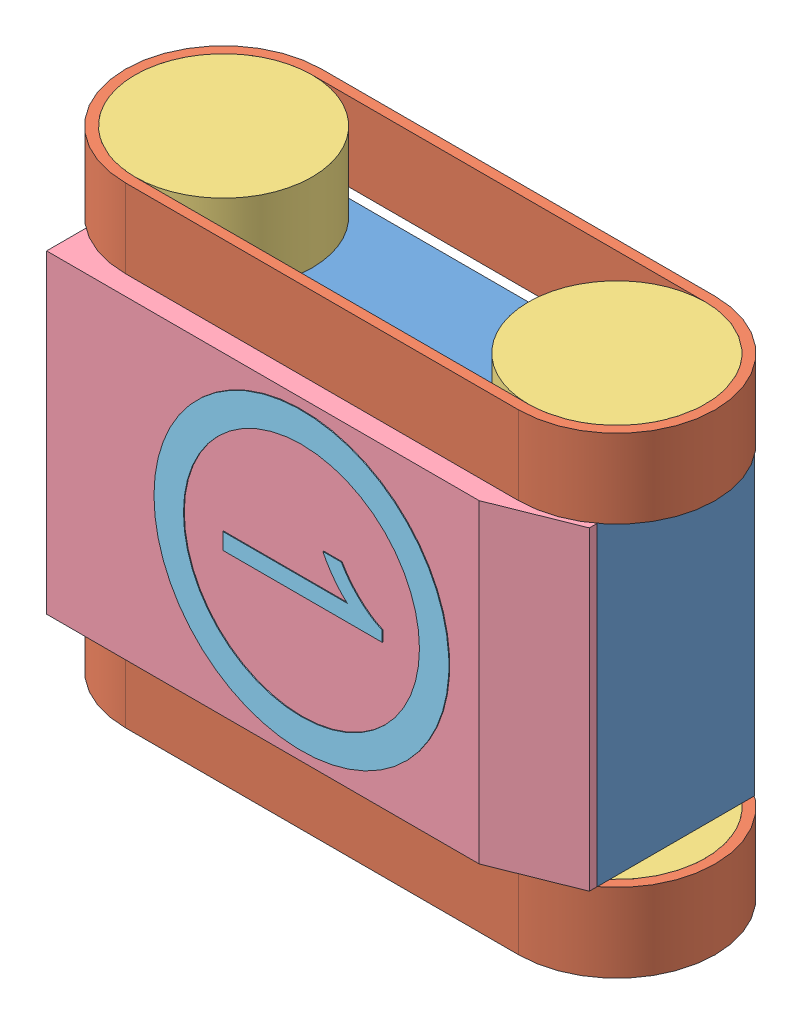
SolidWorks assembly export_robot, configuration Default. Lengths in mm.
Overall size (150 120 55.2).
10 component instances, 5 part files, 3 mates.
Components (placement in the parent):
- robot_base-1: robot_base [Default] at (0 0 5) x (-1 0 0) z (0 1 0) size (150 55.2 120)
  - body-1: body [Default] at origin size (130 40 80)
  - track-1: track [Default] at (0 20 -60) size (150 50 20)
  - track-2: track [Default] at (0 20 40) size (150 50 20)
  - wheel-1: wheel [Default] at (-50 20 40) size (45 45 20)
  - wheel-2: wheel [Default] at (50 20 40) size (45 45 20)
  - wheel-3: wheel [Default] at (-50 20 -60) size (45 45 20)
  - wheel-4: wheel [Default] at (50 20 -60) size (45 45 20)
  - top-1: top [Default] at (0 40 0) x (-1 0 0) z (0 0 -1) size (130 10 80)
  - Part1^robot_base-1: Part1^robot_base [Default] at (0 50 0) x (-1 0 0) z (0 1 0) size (75 75 0.2) (virtual)
Mates (geometry in assembly coordinates):
- Coincident2: coincident anti-aligned: plane of robot_base-1/track-2 through (-50 60 0) normal (0 0 -1)
- Coincident3: coincident anti-aligned: plane of robot_base-1 through (0 0 5) normal (-1 0 0)
- Coincident5: coincident aligned: plane of robot_base-1 through (0 0 5) normal (0 1 0)
